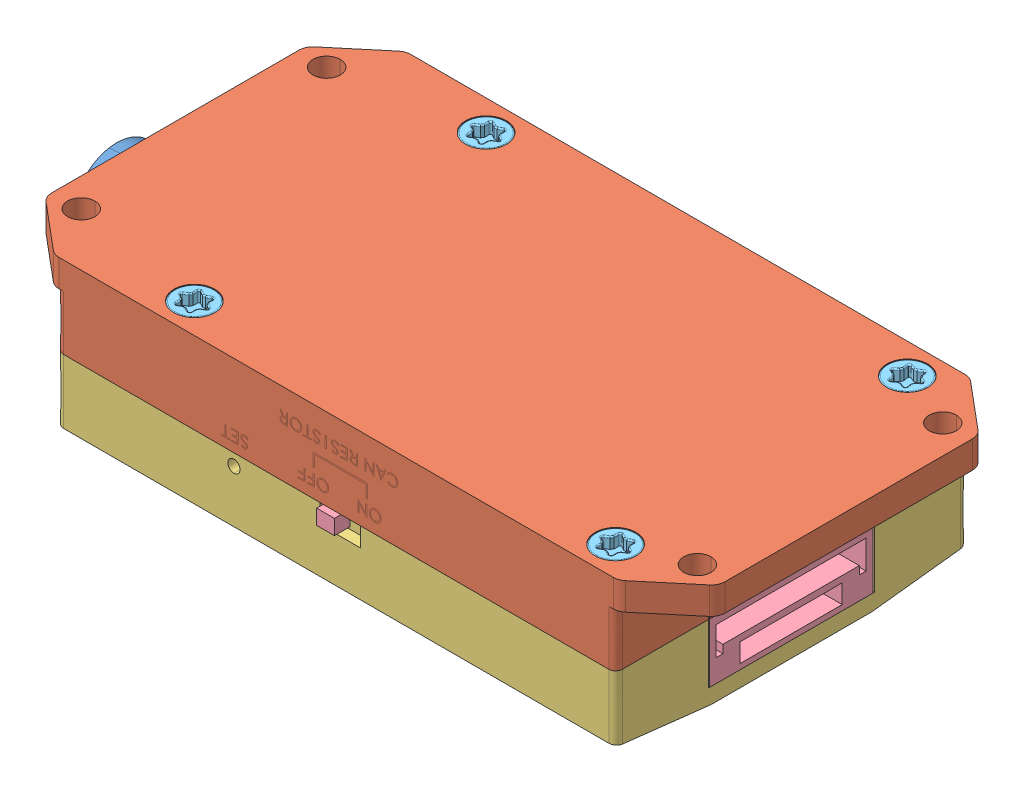
SolidWorks assembly C620无刷电机调速器, configuration 默认. Lengths in mm.
Overall size (53.77 12.66 27.12).
14 component instances, 8 part files, 0 mates.
Components (placement in the parent):
- C620无刷电机调速器.IGS-1: C620无刷电机调速器.IGS [默认] at origin size (53.77 12.66 27.12)
  - 14.STEP.IGS-1: 14.STEP.IGS [默认] at (62.3501 2 4) x (0 0 1) z (1 0 0) (suppressed, hidden)
  - 14.STEP.IGS-2: 14.STEP.IGS [默认] at (62.3501 2 0) x (0 -0.906473 0.422263) z (1 0 0) (suppressed, hidden)
  - 14.STEP.IGS-3: 14.STEP.IGS [默认] at (62.3501 2 -4) x (0 0 1) z (1 0 0) (suppressed, hidden)
  - 1.STEP.IGS-1: 1.STEP.IGS [默认] at (65.7565 2 -18.7519) x (0 0 -1) z (1 0 0) (suppressed, hidden)
  - 6.STEP.IGS-1: 6.STEP.IGS [默认] at (-2.2 39.826 -7.4409) x (0 -0.431667 0.902033) z (-1 0 0) size (8.71 8.7 10.57)
  - 7.STEP.IGS-1: 7.STEP.IGS [默认] at (-1.7 0.6 0) size (49.41 6.03 25.89)
  - 8.STEP.IGS-1: 8.STEP.IGS [默认] at (-1.7 -0.6 0) x (0 -1 0) z (0 0 1) size (6.57 41.01 26.52)
  - 2.STEP.IGS-1: 2.STEP.IGS [默认] at (15.6004 -0.6014 9.8) x (0 0 -1) z (0 1 0) size (24.84 40.81 4.36)
  - 5.STEP.IGS-1: 5.STEP.IGS [默认] at (16.6 -3.6 -10.7) x (-0.36263 0 0.931933) z (-0.931933 0 -0.36263) size (5.61 9.15 3)
  - 5.STEP.IGS-2: 5.STEP.IGS [默认] at (16.6 -3.6 10.7) size (5.61 9.15 3)
  - 5.STEP.IGS-3: 5.STEP.IGS [默认] at (-14.3 -3.6 10.7) size (5.61 9.15 3)
  - 5.STEP.IGS-4: 5.STEP.IGS [默认] at (-14.3 -3.6 -10.7) size (5.61 9.15 3)
  - 10.STEP.IGS-1: 10.STEP.IGS [默认] at (-177.4931 0.4104 -3.9137) x (1 0 0) z (0 -1 0) (suppressed, hidden)
